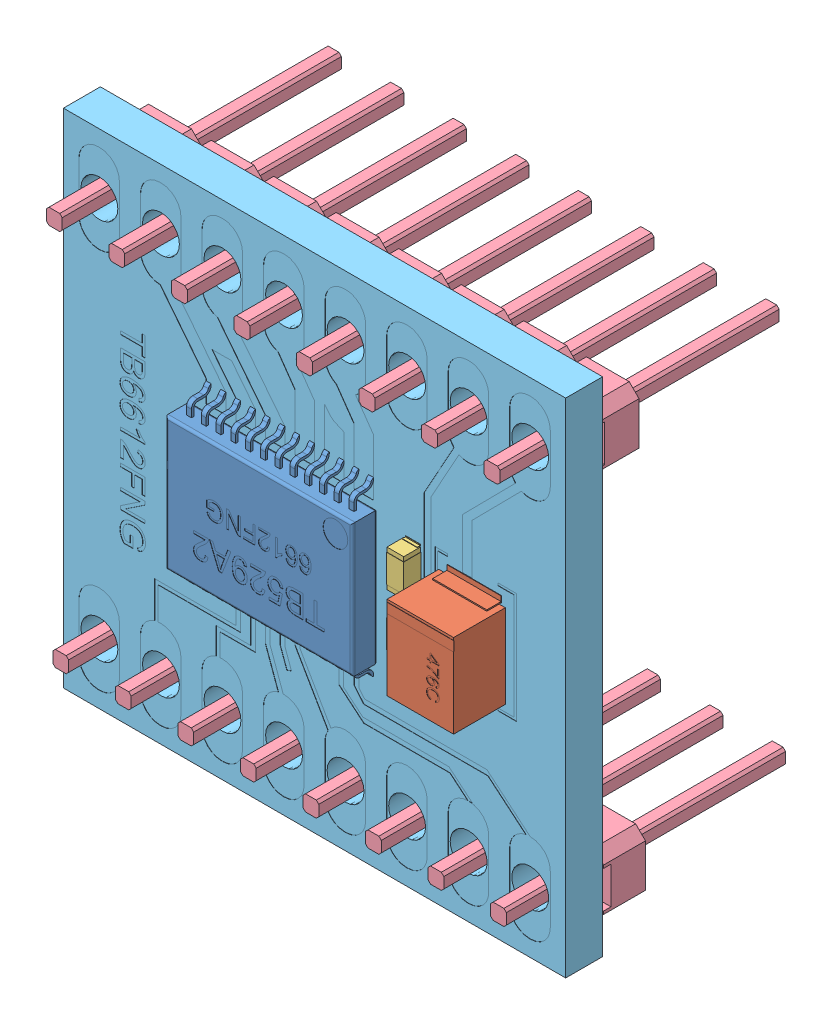
SolidWorks assembly DOBLE PUENTE H, configuration Default. Lengths in mm.
Overall size (20.51 20.4 12.06).
8 component instances, 5 part files, 0 mates.
Components (placement in the parent):
- DOBLE PUENTE H.step-1: DOBLE PUENTE H.step [Default] at origin size (20.51 20.4 12.06)
  - TB6612FNG.step-1: TB6612FNG.step [Default] at (-1.0015 0.0048 1.75) x (-1 0 0) z (0 0 1) size (7.6 7 1.25)
  - capacitor.step-1: capacitor.step [Default] at (6.4979 -0.0001 1.6) x (0 -1 0) z (0 0 1) size (3.9 2.7 2.21)
  - capacitor_v1.step-1: capacitor_v1.step [Default] at (4 -1 1.53) x (0 -1 0) z (0 0 1) size (1.62 0.7 0.73)
  - capacitor_v1.step-2: capacitor_v1.step [Default] at (4 1.3 1.53) x (0 -1 0) z (0 0 1) size (1.62 0.7 0.73)
  - header_8.step-1: header_8.step [Default] at (8.9658 -7.83 -0.0056) x (0 1 0) z (-1 0 0) size (2.54 11.34 20.32)
  - header_8.step-2: header_8.step [Default] at (-9 7.67 0.07) x (0 -1 0) z (1 0 0) size (2.54 11.34 20.32)
  - DOBLE PUENTE H.step-1: DOBLE PUENTE H.step [Default] at origin size (20.4 20.4 1.5)
